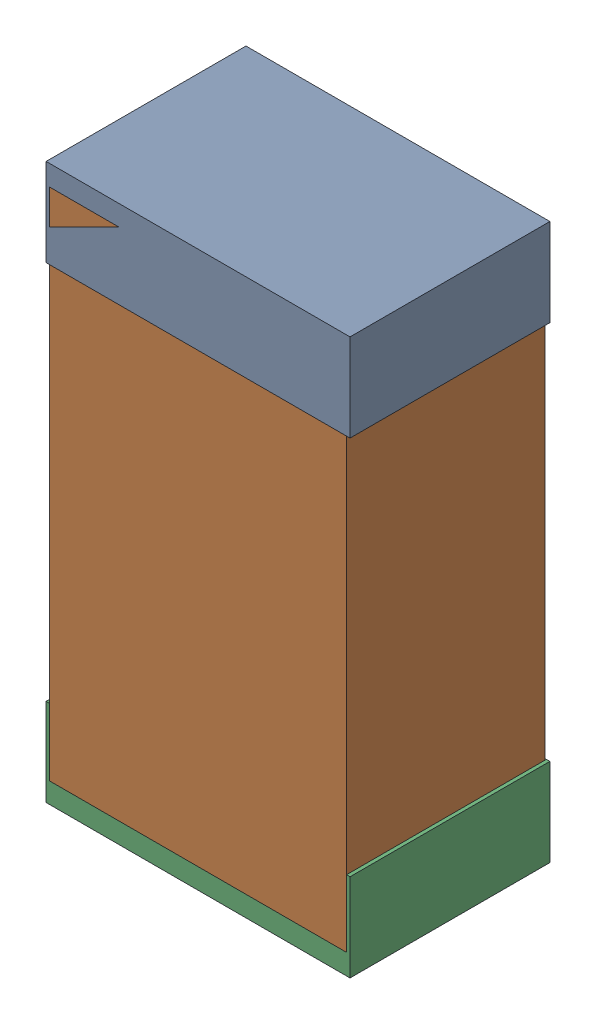
SolidWorks assembly R36Kanaloa_v2.0.0_Motor, configuration Default. Lengths in mm.
Overall size (1.3 2.38 0.85).
6 component instances, 2 part files, 0 mates.
Components (placement in the parent):
- 330415056-1: 330415056 [Default] at (39.116 126.027 -1.9574) size (1.3 0.38 0.85)
  - Extruded_2-1: Extruded_2 [Default] at origin size (1.3 0.38 0.85)
- 334787376-1: 334787376 [Default] at (39.116 125.027 -1.9524) size (1.27 2.2 0.85)
  - Extruded_16-1: Extruded_16 [Default] at origin size (1.27 2.2 0.85)
- 330415056-2: 330415056 [Default] at (39.116 124.027 -1.9574) size (1.3 0.38 0.85)
  - Extruded_2-1: Extruded_2 [Default] at origin size (1.3 0.38 0.85)
